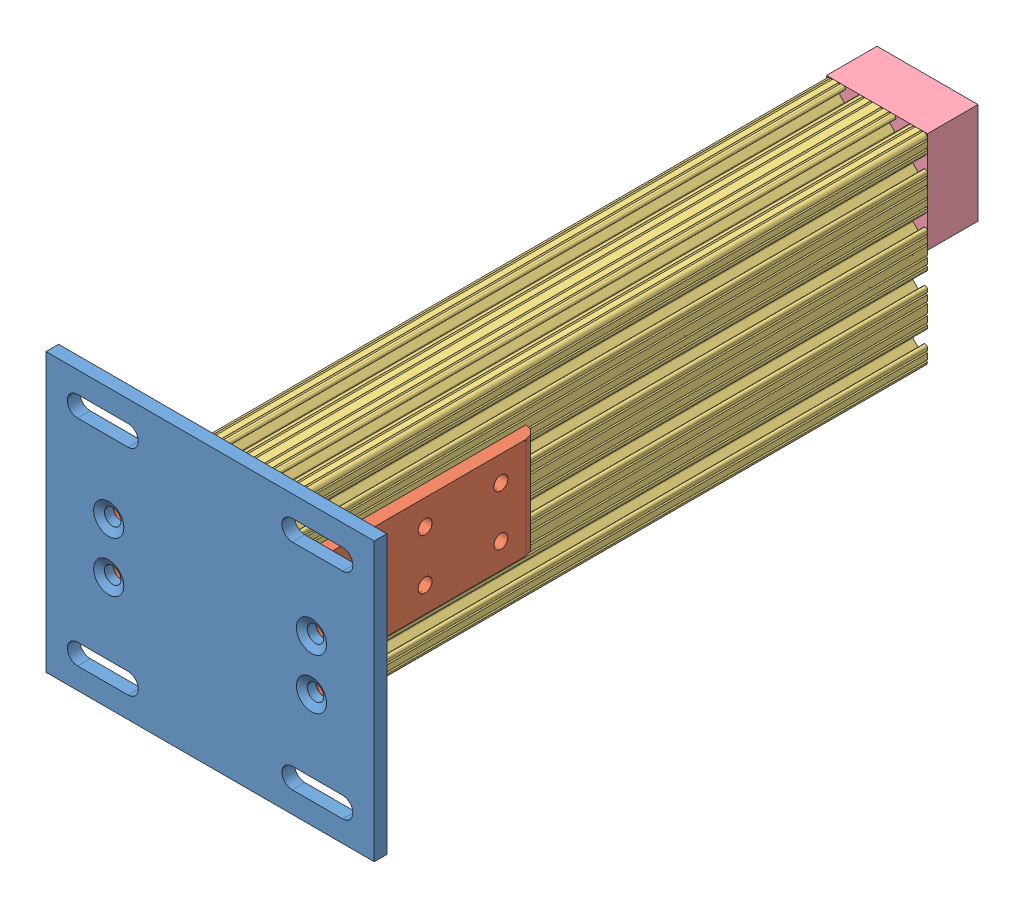
SolidWorks assembly side support leg assembly, configuration Default. Lengths in mm.
Overall size (165.1 139.7 361.06).
6 component instances, 4 part files, 6 mates.
Components (placement in the parent):
- 8020-2387-DEFAULT-1: 8020-2387-DEFAULT [Default] at (-23.3852 -90.5881 115.6024) x (0 1 0) z (-1 0 0) size (139.7 133.35 165.1)
  - 8020-2387-DEFAULT_238708-1: 8020-2387-DEFAULT_238708 [Default] at (-67.1549 7.3704 27.8119) size (139.7 6.35 165.1)
  - 8020-2387-DEFAULT_238509-1: 8020-2387-DEFAULT_238509 [Default] at (9.1264 0.0214 49.7635) x (0 0 1) z (-1 0 0) size (50.8 127 50.8)
  - 8020-2387-DEFAULT_238509-2: 8020-2387-DEFAULT_238509 [Default] at (-41.6736 0.0214 -46.9187) x (0 0 -1) z (1 0 0) size (50.8 127 50.8)
- 8020-2040 leg, 12.965in-1: 8020-2040 leg, 12.965in [Default] at (-37.7108 -144.9607 101.882) size (50.8 101.6 329.31)
- side support leg top bracket rev1-1: side support leg top bracket rev1 [Default] at (0.3892 -56.0607 -227.429) x (0 -1 0) z (1 0 0) size (50.8 25.4 50.8)
Mates (geometry in assembly coordinates):
- Coincident1: coincident anti-aligned: plane of 8020-2387-DEFAULT-1/8020-2387-DEFAULT_238708-1 through (-17.6916 -216.645 75.2053) normal (0 0 -1); plane of 8020-2040 leg, 12.965in-1 through (-43.2948 -45.6409 75.2053) normal (0 0 1)
- Coincident2: coincident anti-aligned: plane of 8020-2387-DEFAULT-1/8020-2387-DEFAULT_238509-1 through (-43.2948 -73.6836 147.977) normal (1 0 0); plane of 8020-2040 leg, 12.965in-1 through (-43.2948 -71.5489 -254.1057) normal (-1 0 0)
- Distance1: distance = 19.05 mm aligned: plane of 8020-2040 leg, 12.965in-1 through (-27.1444 -157.6607 -227.429) normal (0 -1 0); plane of 8020-2387-DEFAULT-1/8020-2387-DEFAULT_238708-1 through (-24.8076 -176.7107 101.882) normal (0 -1 0)
- Coincident3: coincident: plane of 8020-2040 leg, 12.965in-1 through (-50.4108 -104.2191 -227.429) normal (0 0 -1); plane of side support leg top bracket rev1-1 through (-50.4108 -56.0607 -227.429) normal (0 0 1)
- Concentric1: concentric: circle of side support leg top bracket rev1-1; circle of 8020-2040 leg, 12.965in-1
- Concentric2: concentric anti-aligned: circle of 8020-2040 leg, 12.965in-1; circle of side support leg top bracket rev1-1
